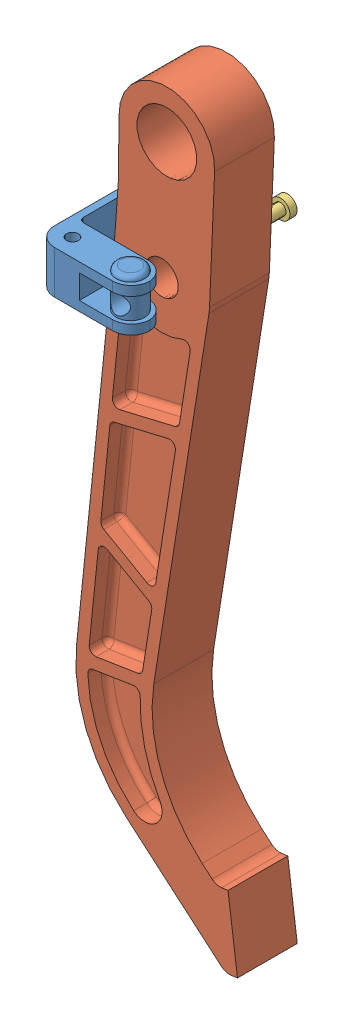
SolidWorks assembly AccPedalDraft, configuration Default. Lengths in mm.
Overall size (158.56 395.4 92.93).
4 component instances, 4 part files, 2 mates.
Components (placement in the parent):
- AccPedalMountDraft-1: AccPedalMountDraft [Default] at (40.7761 71.766 21.2804) size (50.8 25.4 76.2)
- Part1^AccPedalDraft-1: Part1^AccPedalDraft [Default] at origin (virtual)
- AccpedalDraft-1: AccpedalDraft [Default] at (33.7742 43.1192 55.4706) x (0 0 -1) z (0.991631 -0.129102 0) size (31.75 384.44 109.84)
- rod-1: rod [Default] at (33.7742 43.1192 8.3559) x (-0.99992 0.012685 0) z (0.012685 0.99992 0) size (10.16 48.26 10.16)
Mates (geometry in assembly coordinates):
- Concentric1: concentric anti-aligned: cylinder of Accpedal-1 through (33.7742 43.1192 39.5956) axis (0 0 1) radius 8.8004; cylinder of rod-1 through (33.7742 43.1192 52.8059) axis (0 0 -1) radius 3.048
- Concentric2: concentric anti-aligned: cylinder of AccPedalMount-1 through (33.7742 43.1192 21.2804) axis (0 0 1) radius 5.334; cylinder of rod-1 through (33.7742 43.1192 52.8059) axis (0 0 -1) radius 3.048
